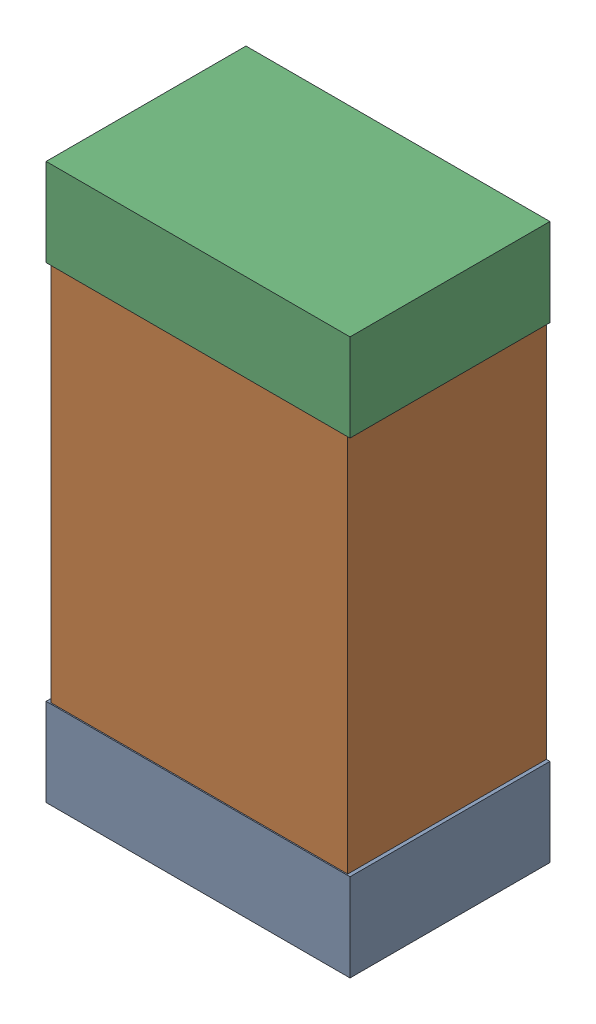
SolidWorks assembly C26Kanaloa_v2.0.0_Power, configuration Default. Lengths in mm.
Overall size (1.3 2.38 0.85).
6 component instances, 2 part files, 0 mates.
Components (placement in the parent):
- 330415056-1: 330415056 [Default] at (59.69 160.036 0) size (1.3 0.38 0.85)
  - Extruded_2-1: Extruded_2 [Default] at origin size (1.3 0.38 0.85)
- 352877008-1: 352877008 [Default] at (59.69 161.036 0) size (1.27 2.2 0.85)
  - Extruded_3-1: Extruded_3 [Default] at origin size (1.27 2.2 0.85)
- 330415056-2: 330415056 [Default] at (59.69 162.036 0) size (1.3 0.38 0.85)
  - Extruded_2-1: Extruded_2 [Default] at origin size (1.3 0.38 0.85)
